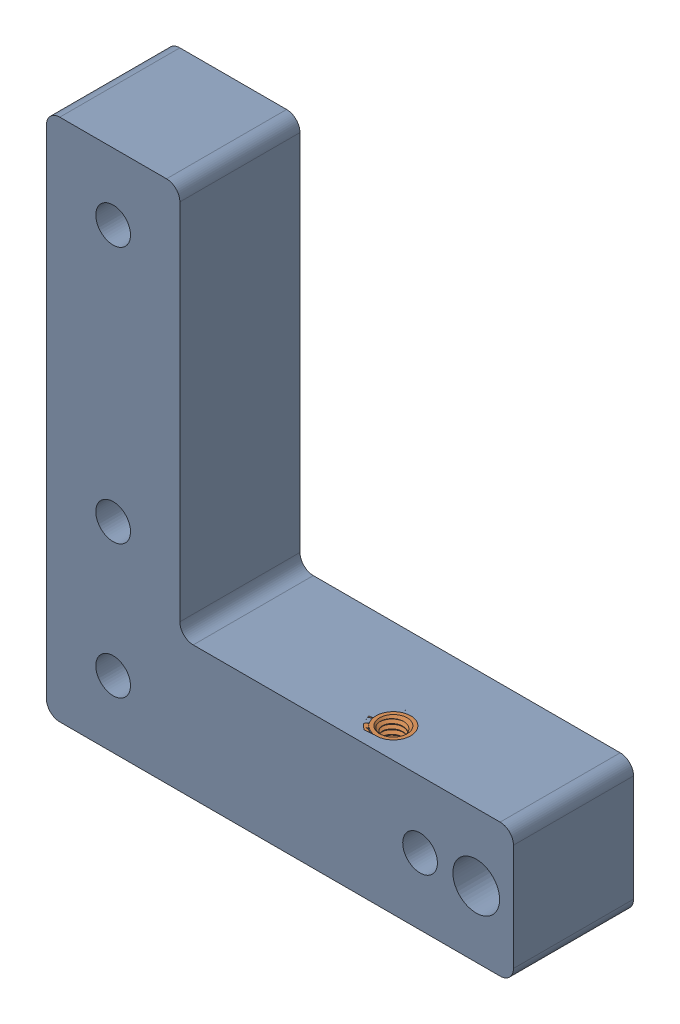
SolidWorks assembly tall_motor_corner_plate_spacer_with_insert, configuration Default. Lengths in mm.
Overall size (70 78.5 18).
2 component instances, 2 part files, 0 mates.
Components (placement in the parent):
- motor_corner_bracket_spacer_Right Motor Corner Bracket Spacer-1: motor_corner_bracket_spacer_Right Motor Corner Bracket Spacer [Default] at (-213.4548 157 -10) x (0 -1 0) z (-1 0 0) size (78.5 18 70)
- m4_heat_set_insert_long_94180A353_94180A353-1: m4_heat_set_insert_long_94180A353_94180A353 [Default] at (-165.9548 20 -4.5) x (0.989318 0 -0.145772) z (0.145772 0 0.989318) size (6.35 8 6.35)
